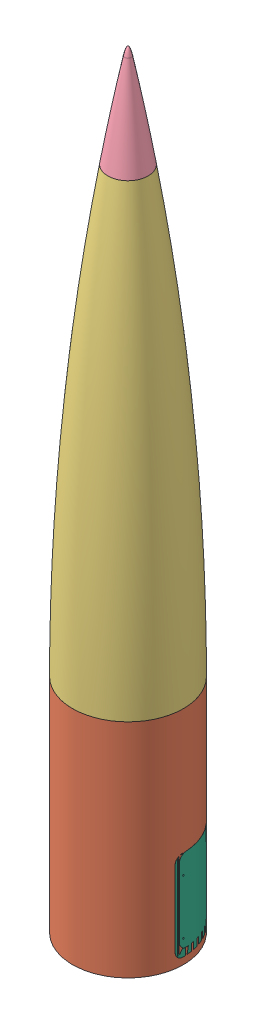
SolidWorks assembly Recovery CAD V4 Assembly, configuration Default. Lengths in mm.
Overall size (203.35 1406.73 203.2).
35 component instances, 22 part files, 20 mates.
Components (placement in the parent):
- Drogue Pods V5-1: Drogue Pods V5 [Default] at origin size (194.51 257.12 194.47)
- 4in Main Chute Tube-2: 4in Main Chute Tube [Default] at (0 150.8722 0) size (107.95 711.2 107.95)
- Hea Set Insert Sled V2-1: Hea Set Insert Sled V2 [Default] at (293.6771 -3.1778 0.4518) x (0 0 1) z (-1 0 0) size (15.05 178 6.39)
- Hea Set Insert Sled V2-2: Hea Set Insert Sled V2 [Default] at (-293.6771 -3.1778 -0.4518) x (0 0 -1) z (1 0 0) size (15.05 178 6.39)
- pilot shute bottom plate-1: pilot shute bottom plate [Default] at (0 848.9928 0) x (0.965608 0 -0.260001) z (0.260001 0 0.965608) size (101.6 7.11 101.6)
- Ballute Cup Redesign-1: Ballute Cup Redesign [Default] at (0 862.4548 0) x (0.987081 0 0.160224) z (-0.160224 0 0.987081) size (106.36 57.15 106.36)
- Bigger_Hatch-1: Bigger_Hatch [Default] at (0 -3.1778 0) size (203.35 166.54 116.46)
- Electronics Bay Assembly-1: Electronics Bay Assembly [Default] at (0 257.7372 0) size (198.12 351.58 198.12)
  - Base 2-3: Base 2 [Default] at origin size (179.07 252.73 179.07)
  - Recovery Slide ALARA-3: Recovery Slide ALARA [Default] at (0 5.08 0) size (111.51 248.38 47.72)
  - Recovery Slide General-3: Recovery Slide General [Default] at (0 5.08 0) x (-1 0 0) z (0 0 -1) size (111.51 248.38 48.37)
  - Top Part-7: Top Part [Default] at (0 259.08 0) x (-1 0 0) z (0 0 1) size (177.23 31.75 179.07)
  - Centering Ring-3: Centering Ring [Baby Shark Recovery Centering Ring] at (0 -1.905 0) x (-1 0 0) z (0 0 -1) size (198.12 3.81 198.12)
  - ALARA PCB-4: ALARA PCB [Default] at (24.892 55.626 -62.484) x (-1 0 0) z (0 1 0) size (49.78 1.52 159.26)
  - Eggtimer Proton-6: Eggtimer Proton [Default] at (20.327 62.2633 55.9361) x (0 1 0) z (0.939693 0 -0.34202) size (83.27 15.04 30.57)
  - Eggtimer Proton-7: Eggtimer Proton [Default] at (-29.7314 62.2633 51.5566) x (0 1 0) z (0.866025 0 0.5) size (83.27 15.04 30.57)
  - Eggtimer TRS Tracker-9: Eggtimer TRS Tracker [Default] at (-10.3007 182.8899 58.6168) x (0.000689 -1 0.000122) z (-0.984808 -0.0007 -0.173648) size (216.46 11.11 32.77)
  - Telemetry Module-5: Telemetry Module [Default] at (29.7575 190.5032 51.5415) x (0 -1 0) z (-0.866025 0 0.5) size (161.4 7.84 19.04)
  - Turnigy nano-tech 1200mAh 2S 15_25C Lipo 2-13: Turnigy nano-tech 1200mAh 2S 15_25C Lipo 2 [Default] at (-46.5329 252.73 35.0242) x (-0.422618 0 -0.906308) z (0 1 0) size (19.71 10.41 127.79)
  - Turnigy nano-tech 1200mAh 2S 15_25C Lipo 2-14: Turnigy nano-tech 1200mAh 2S 15_25C Lipo 2 [Default] at (-55.9712 252.73 39.4254) x (-0.422618 0 -0.906308) z (0 1 0) size (19.71 10.41 127.79)
  - Turnigy nano-tech 1200mAh 2S 15_25C Lipo 2-15: Turnigy nano-tech 1200mAh 2S 15_25C Lipo 2 [Default] at (65.4095 252.73 43.8265) x (0.422618 0 -0.906308) z (0 1 0) size (19.71 10.41 127.79)
  - Turnigy nano-tech 1200mAh 2S 15_25C Lipo 2-16: Turnigy nano-tech 1200mAh 2S 15_25C Lipo 2 [Default] at (55.9712 252.73 39.4254) x (0.422618 0 -0.906308) z (0 1 0) size (19.71 10.41 127.79)
  - Charge Tube-1: Charge Tube [Default] at (76.2 74.93 0) x (0.797278 0 0.603612) z (-0.603612 0 0.797278) size (26.67 177.8 26.67)
  - Charge Tube-2: Charge Tube [Default] at (-76.2 74.93 0) x (-0.785022 0 0.619467) z (-0.619467 0 -0.785022) size (26.67 177.8 26.67)
  - Turnigy nano-tech 1200mAh 2S 15_25C Lipo 2-17: Turnigy nano-tech 1200mAh 2S 15_25C Lipo 2 [Default] at (-54.8629 252.73 -17.1605) x (0.422618 0 -0.906308) z (0 1 0) size (19.71 10.41 127.79)
  - Turnigy nano-tech 1200mAh 2S 15_25C Lipo 2-18: Turnigy nano-tech 1200mAh 2S 15_25C Lipo 2 [Default] at (-64.3012 252.73 -21.5617) x (0.422618 0 -0.906308) z (0 1 0) size (19.71 10.41 127.79)
  - Turnigy nano-tech 1200mAh 2S 15_25C Lipo 2-19: Turnigy nano-tech 1200mAh 2S 15_25C Lipo 2 [Default] at (73.7395 252.73 -25.9628) x (-0.422618 0 -0.906308) z (0 1 0) size (19.71 10.41 127.79)
  - Turnigy nano-tech 1200mAh 2S 15_25C Lipo 2-20: Turnigy nano-tech 1200mAh 2S 15_25C Lipo 2 [Default] at (64.3012 252.73 -21.5617) x (-0.422618 0 -0.906308) z (0 1 0) size (19.71 10.41 127.79)
  - 97171A310_Brass Heat-Set Inserts for Plastic-1: 97171A310_Brass Heat-Set Inserts for Plastic [97171A310] at (-23.7651 232.2195 53.378) x (0.661787 -0.740554 0.116691) z (-0.729304 -0.671996 -0.128596) size (5.54 6.42 5.54)
  - 97171A310_Brass Heat-Set Inserts for Plastic-2: 97171A310_Brass Heat-Set Inserts for Plastic [97171A310] at (-39.7766 249.3298 41.9158) x (0.543007 0 -0.839728) z (0.839728 0 0.543007) size (5.54 6.42 5.54)
  - Ebay Hatch V2-1: Ebay Hatch V2 [Default] at (0 262.382 0) x (-1 0 0) z (0 0 1) size (185.42 262.38 185.42)
- COTS 8in tube-1: COTS 8in tube [Default] at (0 -15.8778 0) size (203.2 406.4 203.2)
- COTS Tangent Ogive Nose Cone with metal tip - 8 inch-1: COTS Tangent Ogive Nose Cone with metal tip - 8 inch [Default] at (0 390.5222 0) x (0 1 0) z (1 0 0) size (1101.93 203.2 203.2)
  - Tangent_Ogive_Nosecone_01-1: Tangent_Ogive_Nosecone_01 [40in] x (0 0 -1) z (0 -1 0) size (203.2 914.4 203.2)
  - Tangent_Ogive_Nosecone_02-1: Tangent_Ogive_Nosecone_02 [40in] x (0 0 -1) z (0 -1 0) size (73.62 187.53 73.62)
Mates (geometry in assembly coordinates):
- Coincident1: coincident anti-aligned: plane of Drogue Pods V5-1 through (0 150.8722 0) normal (0 1 0); plane of 4in Main Chute Tube-2 through (0 150.8722 0) normal (0 -1 0)
- Concentric1: concentric anti-aligned: cylinder of Drogue Pods V5-1 through (0 -4.9961 0) axis (0 1 0) radius 53.34; cylinder of 4in Main Chute Tube-2 through (0 862.0722 0) axis (0 -1 0) radius 53.975
- Coincident2: coincident anti-aligned: plane of Drogue Pods V5-1 through (90.4771 253.9421 0) normal (1 0 0); plane of Hea Set Insert Sled V2-1 through (90.4771 174.8222 8.4528) normal (-1 0 0)
- Coincident3: coincident aligned: plane of Drogue Pods V5-1 through (0 -3.1778 0) normal (0 -1 0); plane of Hea Set Insert Sled V2-1 through (-106.3729 -3.1778 0.4518) normal (0 -1 0)
- Concentric2: concentric anti-aligned: cylinder of Drogue Pods V5-1 through (91.7471 253.9421 6.7055) axis (0 1 0) radius 1.27; cylinder of Hea Set Insert Sled V2-1 through (91.7471 174.8222 6.7055) axis (0 -1 0) radius 1.27
- Coincident4: coincident anti-aligned: plane of Drogue Pods V5-1 through (-90.4771 253.9421 0) normal (-1 0 0); plane of Hea Set Insert Sled V2-2 through (-90.4771 174.8222 -8.4528) normal (1 0 0)
- Coincident5: coincident aligned: plane of Drogue Pods V5-1 through (0 -3.1778 0) normal (0 -1 0); plane of Hea Set Insert Sled V2-2 through (106.3729 -3.1778 -0.4518) normal (0 -1 0)
- Concentric3: concentric aligned: cylinder of Drogue Pods V5-1 through (-91.7471 253.9421 -6.7055) axis (0 -1 0) radius 1.27; cylinder of Hea Set Insert Sled V2-2 through (-91.7471 174.8222 -6.7055) axis (0 -1 0) radius 1.27
- Concentric4: concentric aligned: cylinder of 4in Main Chute Tube-2 through (0 862.0722 0) axis (0 -1 0) radius 50.8; cylinder of pilot shute bottom plate-1 through (0 856.1048 0) axis (0 -1 0) radius 50.8
- Concentric5: concentric anti-aligned: cylinder of 4in Main Chute Tube-2 through (36.8656 852.5472 -63.8531) axis (-0.5 0 0.866025) radius 1.5875; cylinder of pilot shute bottom plate-1 through (25.4 852.5472 -43.9941) axis (0.5 0 -0.866025) radius 1.1303
- Coincident6: coincident anti-aligned: plane of pilot shute bottom plate-1 through (0 856.1048 0) normal (0 1 0); plane of Ballute Cup Redesign-1 through (0 856.1048 0) normal (0 -1 0)
- Parallel1: parallel anti-aligned: plane of 4in Main Chute Tube-2 through (0 862.0722 0) normal (0 1 0); plane of Ballute Cup Redesign-1 through (0 862.4548 0) normal (0 -1 0)
- Coincident8: coincident anti-aligned: circle of pilot shute bottom plate-1; circle of Ballute Cup Redesign-1
- Concentric7: concentric aligned: cylinder of Drogue Pods V5-1 through (0 280.968 0) axis (0 -1 0) radius 97.155; cylinder of Bigger_Hatch-1 through (0 161.9222 0) axis (0 -1 0) radius 99.06
- Coincident9: coincident aligned: plane of Drogue Pods V5-1 through (0 -3.1778 0) normal (0 -1 0); plane of Bigger_Hatch-1 through (0 -3.1778 0) normal (0 -1 0)
- Concentric8: concentric anti-aligned: circle of Drogue Pods V5-1; circle of Electronics Bay Assembly-1/Centering Ring-3
- Concentric10: concentric aligned: cylinder of Drogue Pods V5-1 through (0 280.968 0) axis (0 -1 0) radius 97.155; cylinder of COTS 8in tube-1 through (0 390.5222 0) axis (0 -1 0) radius 98.425
- Coincident11: coincident anti-aligned: plane of Bigger_Hatch-1 through (0 161.9222 0) normal (0 1 0); plane of COTS 8in tube-1 through (0 161.9222 0) normal (0 -1 0)
- Coincident12: coincident anti-aligned: plane of COTS 8in tube-1 through (0 390.5222 0) normal (0 1 0); plane of COTS Tangent Ogive Nose Cone with metal tip - 8 inch-1/Tangent_Ogive_Nosecone_01-1 through (0 390.5222 0) normal (0 -1 0)
- Concentric11: concentric aligned: cylinder of COTS 8in tube-1 through (0 390.5222 0) axis (0 -1 0) radius 98.425; cylinder of COTS Tangent Ogive Nose Cone with metal tip - 8 inch-1/Tangent_Ogive_Nosecone_01-1 through (0 390.5222 0) axis (0 -1 0) radius 98.425
